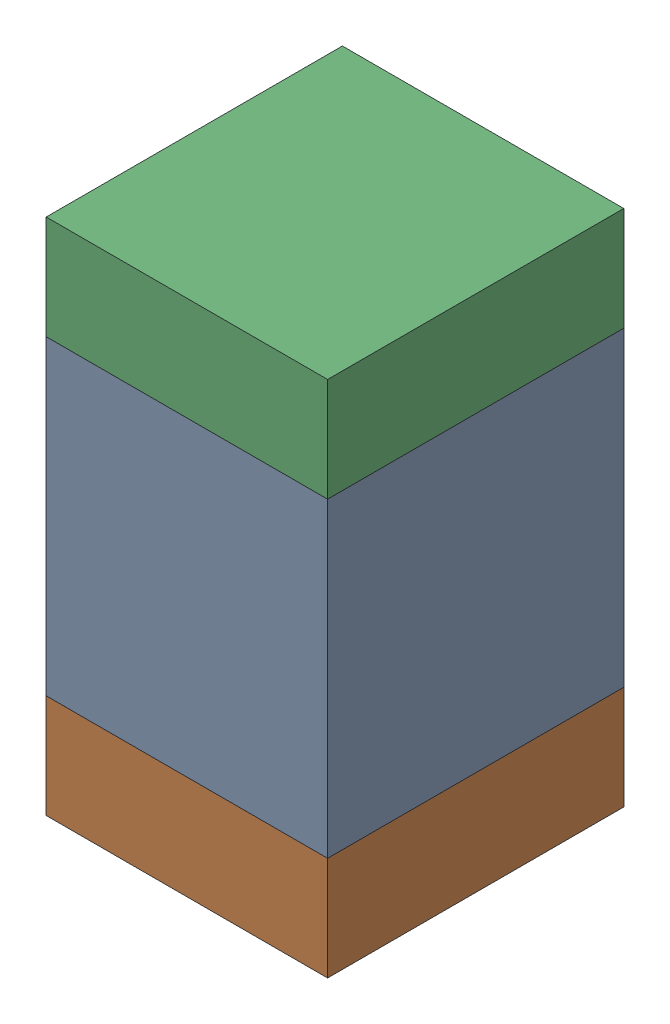
SolidWorks assembly C4, configuration Default. Lengths in mm.
Overall size (0.95 1.75 1).
6 component instances, 2 part files, 0 mates.
Components (placement in the parent):
- 959208528-1: 959208528 [Default] at (127.791 83.885 0) size (0.95 1.05 1)
  - Extruded-15-1: Extruded-15 [Default] at origin size (0.95 1.05 1)
- 959208664-1: 959208664 [Default] at (127.791 83.185 0) size (0.95 0.35 1)
  - Extruded-14-1: Extruded-14 [Default] at origin size (0.95 0.35 1)
- 959208664-2: 959208664 [Default] at (127.791 84.585 0) size (0.95 0.35 1)
  - Extruded-14-1: Extruded-14 [Default] at origin size (0.95 0.35 1)
